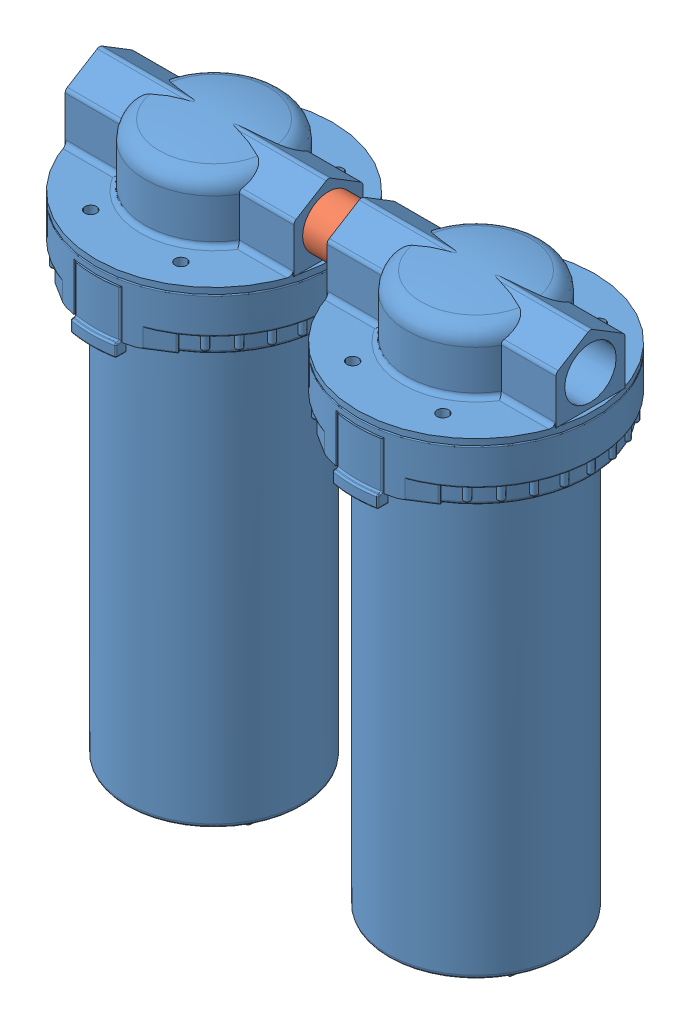
SolidWorks assembly ReadingTech_3P-060-M04-DCP, configuration Default. Lengths in mm.
Overall size (206.63 246.51 99.95).
3 component instances, 2 part files, 3 mates.
Components (placement in the parent):
- ReadingTech_3P-060-M04-P-1: ReadingTech_3P-060-M04-P [Default] at (-36.3185 -100.8596 13.2409) size (98.17 246.51 99.95)
- ReadingTech_3P-060-M04-P-2: ReadingTech_3P-060-M04-P [Default] at (72.1395 -100.8596 13.2409) size (98.17 246.51 99.95)
- ReadingTech- 60cfm_connector_.5in-1: ReadingTech- 60cfm_connector_.5in [Default] at (24.7685 115.0404 13.2409) x (0 1 0) z (0 0 1) size (21.34 13.72 21.34)
Mates (geometry in assembly coordinates):
- Coincident1: coincident anti-aligned: circle of ReadingTech_3P-060-M04-P-1; circle of ReadingTech- 60cfm_connector_.5in-1
- Coincident2: coincident aligned: circle of ReadingTech_3P-060-M04-P-2; circle of ReadingTech- 60cfm_connector_.5in-1
- Coincident3: coincident aligned: plane of ReadingTech_3P-060-M04-P-1 through (11.0525 102.3404 27.5284) normal (0 0 1); plane of ReadingTech_3P-060-M04-P-2 through (119.5105 102.3404 27.5284) normal (0 0 1)
